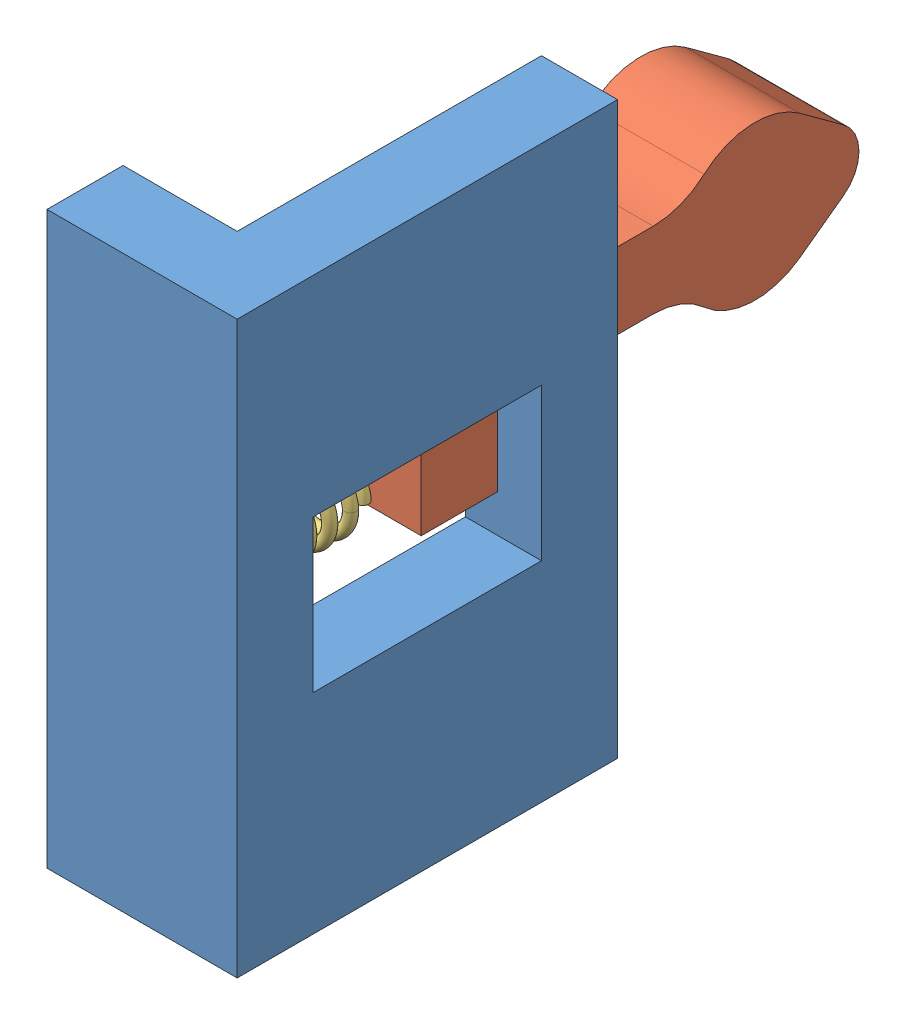
SolidWorks assembly inhibitswitchassembly, configuration Default. Lengths in mm.
Overall size (6.15 15 19.5).
3 component instances, 3 part files, 2 mates.
Components (placement in the parent):
- inhibitswitchholder-1: inhibitswitchholder [Default] at (-7.3985 12.9896 -4.9209) size (5 15 10)
- inhibitswitch-1: inhibitswitch [Default] at (-8.0469 12.9896 -12.9579) x (0 0 1) z (-1 0 0) size (13.51 4.06 5)
- 8969T106_316 STAINLESS STEEL COMPRESSION SPRING-1: 8969T106_316 STAINLESS STEEL COMPRESSION SPRING [8969T106] at (-7.5767 12.9896 -2.0733) size (2.24 2.24 3.18)
Mates (geometry in assembly coordinates):
- Coincident2: coincident: plane of inhibitswitchholder-1 through (-7.3985 12.9896 -4.9209) normal (0 1 0); plane of 8969T106_316 STAINLESS STEEL COMPRESSION SPRING-1 through (-7.5767 12.9896 -2.0733) normal (0 1 0)
- Coincident3: coincident: plane of inhibitswitchholder-1 through (-7.3985 12.9896 -4.9209) normal (0 1 0); plane of inhibitswitch-1 through (-8.0469 12.9896 -12.9579) normal (0 1 0)
